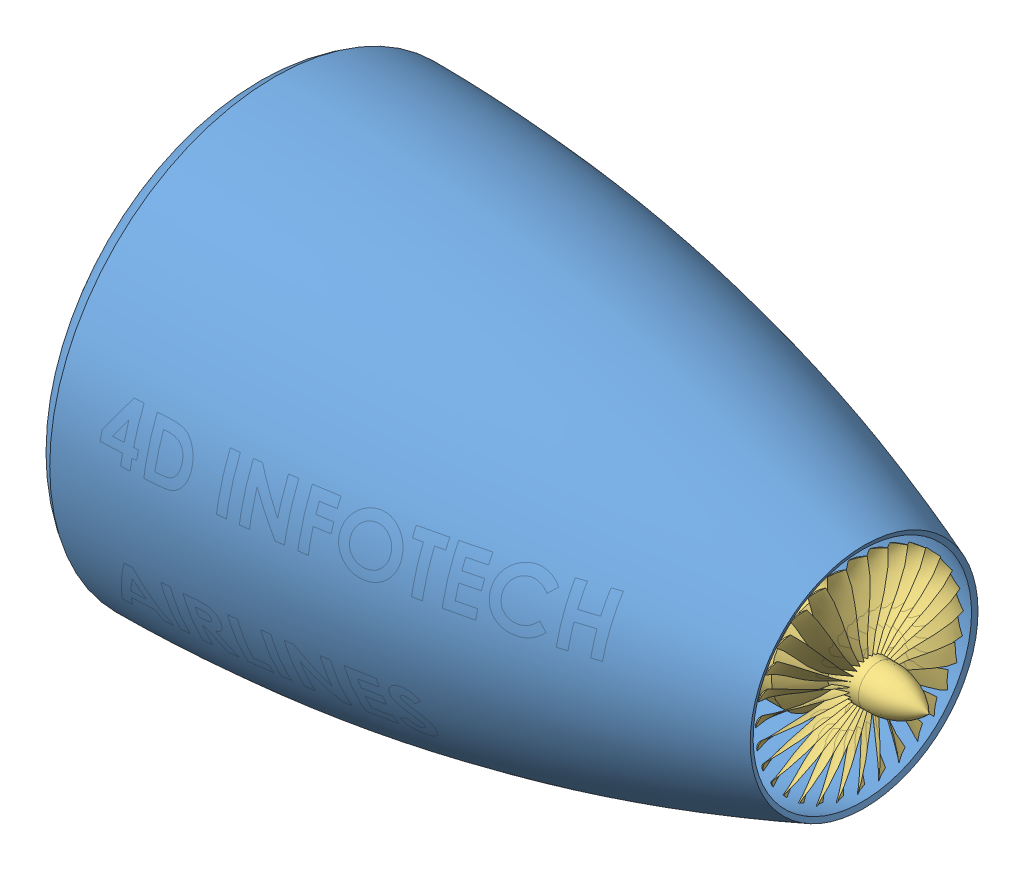
SolidWorks assembly Jet Engine, configuration Default. Lengths in mm.
Overall size (778 458.15 457.54).
3 component instances, 3 part files, 5 mates.
Components (placement in the parent):
- Housing-1: Housing [Default] at (-48.4108 308.5645 479.5623) size (604.51 444.97 444.97)
- Propeller-1: Propeller [Default] at (-180.4311 308.5645 479.5623) x (0 -0.414806 0.90991) z (-1 0 0) size (345 346.23 166)
- Shaft-1: Shaft [Default] at (-52.4311 308.5645 479.5623) x (1 0 0) z (0 0.414806 -0.90991) size (650 200 200.42)
Mates (geometry in assembly coordinates):
- Concentric2: concentric: cylinder of Propeller-1 through (-52.4311 308.5645 479.5623) axis (1 0 0) radius 20; cylinder of Shaft-1 through (547.5689 308.5645 479.5623) axis (1 0 0) radius 20
- Coincident1: coincident: plane of Propeller-1 through (-52.4311 308.5645 479.5623) normal (1 0 0); plane of Shaft-1 through (-52.4311 308.5645 479.5623) normal (-1 0 0)
- Concentric3: concentric aligned: circle of Housing-1; cylinder of Shaft-1 through (547.5689 308.5645 479.5623) axis (1 0 0) radius 48.04
- Distance1: distance = 30 mm anti-aligned: plane of Shaft-1 through (47.5689 290.3663 471.2662) normal (-1 0 0); plane of Housing-1 through (17.5689 308.5645 479.5623) normal (1 0 0)
- Coincident3: coincident anti-aligned: plane of Propeller-1; plane of Shaft-1 through (-52.4311 308.5645 479.5623) normal (0 0.90991 0.414806)
